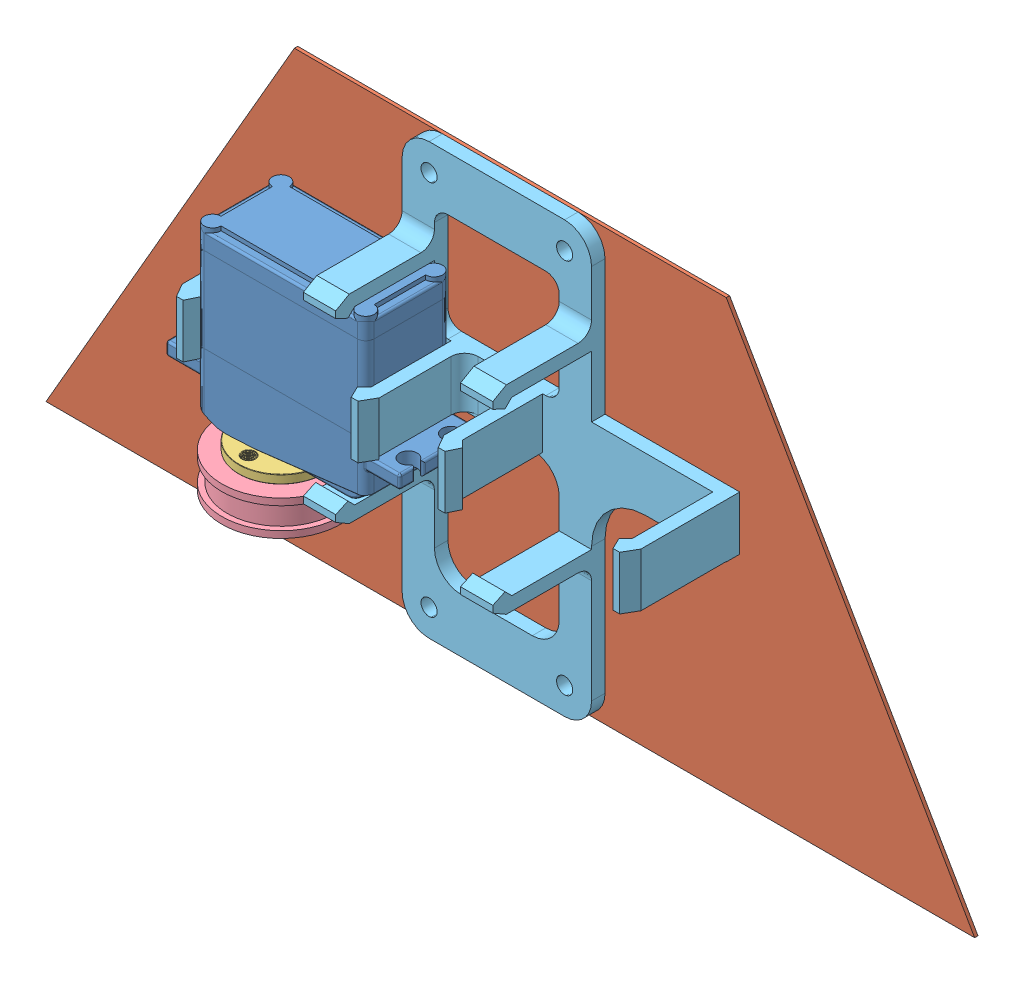
SolidWorks assembly robo_cap_assembly, configuration Default. Lengths in mm.
Overall size (218.9 101.41 27.99).
6 component instances, 6 part files, 21 mates.
Components (placement in the parent):
- LewanSoul LD-20M  Servo 20kg-1: LewanSoul LD-20M  Servo 20kg [Default] at (78.597 77.765 14.0188) x (-1 0 0) z (0 0 1) size (55.1 45.65 20.12)
- Part2^robo_cap_assembly-1: Part2^robo_cap_assembly [Default] at origin size (218.9 101.41 0.79) (virtual)
- Part3^robo_cap_assembly-1: Part3^robo_cap_assembly [Default] at (0 0 0.7937) size (25.4 101.41 0) (virtual)
- servo horn-1: servo horn [Default] at (68.647 31.115 14.0188) x (0.995107 0 0.098804) z (0 1 0) size (20 20 4.88)
- spool-1: spool [Default] at (3.8444 35.7559 1.5718) size (27.94 8.25 27.94)
- motor_holder_v1-1: motor_holder_v1 [Default] at (0 0 0.7937) size (108.15 101.41 26.45)
Mates (geometry in assembly coordinates):
- InPlace1: in place: plane of Part2^robo_cap_assembly-1 through (0 0 0) normal (0 0 1); moOrthogonalPlaneRef_w of Part2^robo_cap_assembly-1 through (0 0 0) normal (0 1 0); plane of Part2^robo_cap_assembly-1 through (0 0 0) normal (1 0 0); unknown of Part2^robo_cap_assembly-1
- Coincident1: coincident aligned: 
- Coincident2: coincident aligned: plane of Part2^Assem1-1 through (0 0 0) normal (0 1 0)
- Coincident3: coincident anti-aligned: plane of Part2^Assem1-1 through (0 0 0) normal (1 0 0)
- InPlace2: in place: plane of Part2^robo_cap_assembly-1 through (0 0 0.7937) normal (0 0 1); plane of ? through (0 0 0.7937) normal (0 0 1); plane of Part2^robo_cap_assembly-1 through (0 0 0.7937) normal (0 0 1); plane of ? through (0 0 0.7937) normal (0 1 0); plane of Part2^robo_cap_assembly-1 through (0 0 0.7937) normal (0 0 1); plane of ? through (0 0 0.7937) normal (1 0 0); plane of Part2^robo_cap_assembly-1 through (0 0 0.7937) normal (0 0 1); unknown of ?
- Coincident4: coincident aligned: plane of ?; plane of ?
- Coincident5: coincident aligned: moOrthogonalPlaneRef_w of Part2^Assem1-1 through (0 0 0.7937) normal (0 1 0); plane of Part3^Assem1-1 through (0 0 0.7937) normal (0 1 0)
- Coincident6: coincident anti-aligned: moOrthogonalPlaneRef_w of Part2^Assem1-1 through (0 0 0.7937) normal (-1 0 0); plane of Part3^Assem1-1 through (0 0 0.7937) normal (1 0 0)
- Parallel2: parallel anti-aligned: plane of LewanSoul LD-20M  Servo 20kg-1 through (58.547 37.265 3.9688) normal (0 0 -1); plane of Part2^Assem1-1 through (0 0 0.7937) normal (0 0 1)
- Distance1: distance = 3.175 mm anti-aligned: plane of LewanSoul LD-20M  Servo 20kg-1 through (58.547 37.265 3.9688) normal (0 0 -1); plane of Part2^Assem1-1 through (0 0 0.7937) normal (0 0 1)
- Parallel3: parallel aligned: plane of LewanSoul LD-20M  Servo 20kg-1 through (78.597 77.765 14.0188) normal (0 1 0); plane of Part2^Assem1-1 through (58.547 101.4064 0.7937) normal (0 1 0)
- Coincident10: coincident: plane of LewanSoul LD-20M  Servo 20kg-1 through (58.547 37.265 24.0688) normal (-1 0 0); line of Part3^Assem1-1 through (58.547 101.4064 0.7937) axis (0 -1 0)
- Concentric1: concentric anti-aligned: circle of LewanSoul LD-20M  Servo 20kg-1; circle of servo horn-1
- Coincident11: coincident anti-aligned: plane of LewanSoul LD-20M  Servo 20kg-1 through (68.647 32.115 14.0188) normal (0 -1 0); plane of servo horn-1 through (68.647 32.115 14.0188) normal (0 1 0)
- InPlace3: in place: plane of Part2^robo_cap_assembly-1 through (0 0 0.7937) normal (0 0 1); plane of ? through (0 0 0.7937) normal (0 0 1); plane of Part2^robo_cap_assembly-1 through (0 0 0.7937) normal (0 0 1); plane of ? through (0 0 0.7937) normal (0 1 0); plane of Part2^robo_cap_assembly-1 through (0 0 0.7937) normal (0 0 1); plane of ? through (0 0 0.7937) normal (1 0 0); plane of Part2^robo_cap_assembly-1 through (0 0 0.7937) normal (0 0 1); unknown of ?
- Coincident12: coincident aligned: plane of assembly through (0 0 0.7937) normal (0 0 1); plane of assembly through (0 0 0.7937) normal (0 0 1)
- Coincident13: coincident aligned: moOrthogonalPlaneRef_w of Part2^robo_cap_assembly-1 through (0 0 0.7937) normal (0 1 0); plane of Part5^robo_cap_assembly-1 through (0 0 0.7937) normal (0 1 0)
- Coincident14: coincident anti-aligned: moOrthogonalPlaneRef_w of Part2^robo_cap_assembly-1 through (0 0 0.7937) normal (-1 0 0); plane of Part5^robo_cap_assembly-1 through (0 0 0.7937) normal (1 0 0)
- Coincident15: coincident anti-aligned: plane of servo horn-1 through (68.647 31.115 14.0188) normal (0 -1 0); plane of spool-1 through (68.647 31.115 14.0188) normal (0 1 0)
- Concentric2: concentric aligned: cylinder of servo horn-1; cylinder of spool-1 through (68.647 29.5275 14.0188) axis (0 1 0) radius 3.81
- Distance4: distance = 22.86 mm aligned: plane of Part2^robo_cap_assembly-1 through (0 0 0.7937) normal (0 -1 0); plane of spool-1 through (68.647 22.86 14.0188) normal (0 -1 0)
